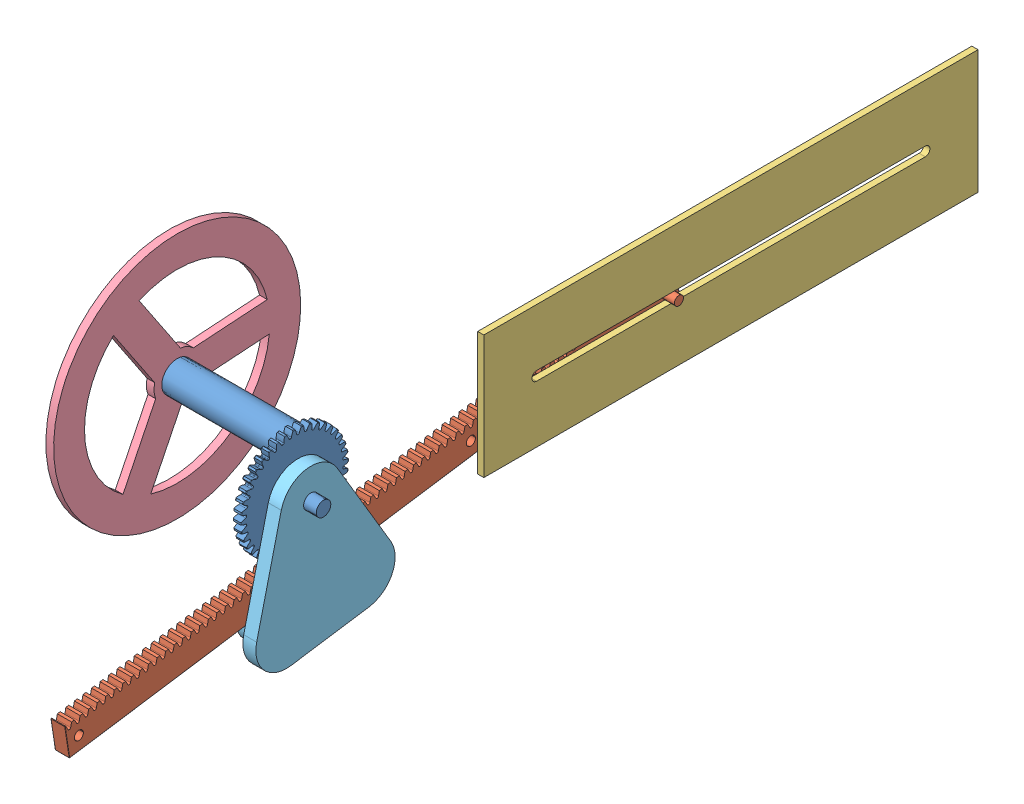
SolidWorks assembly ProgressiveSteering, configuration Default. Lengths in mm.
Overall size (68.98 136.01 372.88).
5 component instances, 5 part files, 15 mates.
Components (placement in the parent):
- SI_sdpsi_s1268z-024s040-2: SI_sdpsi_s1268z-024s040 [Default] at (1.5875 -11.3961 5.6053) x (1 0 0) z (0 -0.441363 -0.897329) size (65.8 44.45 44.45)
- SI_sdpsi_s1811y-rc-1a-1: SI_sdpsi_s1811y-rc-1a [Default] at (1.5875 -33.5524 -25.0715) x (0 -0.14912 0.988819) z (-1 0 0) size (254.01 12.19 10.85)
- slot-1: slot [Default] at (116.0145 -19.3663 -197.6025) x (0 0 1) z (-1 0 0) size (203.2 50.8 2.54)
- steering wheel-1: steering wheel [Default] at (-55.5625 0 0) x (0 0.441363 0.897329) z (1 0 0) size (101.6 101.6 3.18)
- Part1^ProgressiveSteering-1: Part1^ProgressiveSteering [Default] at (4.5085 -30.7069 -43.9399) x (0 0.14912 -0.988819) z (1 0 0) size (57.65 65.11 12.7) (virtual)
Mates (geometry in assembly coordinates):
- Coincident6: coincident anti-aligned: circle of SI_sdpsi_s1268z-024s040-2
- Coincident8: coincident: point of SI_sdpsi_s1268z-024s040-2; point of assembly
- Coincident13: coincident anti-aligned: plane of SI_sdpsi_s1268z-024s040-2 through (1.5875 -11.3961 5.6053) normal (1 0 0); plane of SI_sdpsi_s1811y-rc-1a-1 through (1.5875 -33.5524 -25.0715) normal (-1 0 0)
- Distance1: distance = 21.082 mm: line of assembly; point of SI_sdpsi_s1268z-024s040-2; line of SI_sdpsi_s1811y-rc-1a-1 through (1.5875 -47.4413 103.6472) axis (0 0.14912 -0.988819)
- RackPinionMate2: rack pinion = 45.212 mm: line of SI_sdpsi_s1811y-rc-1a-1 through (-1.3335 -20.5354 -151.4161) axis (0 -0.14912 0.988819); cylinder of SI_sdpsi_s1268z-024s040-2 through (0 -11.3961 5.6053) axis (1 0 0) radius 22.225
- Tangent1: tangent: cylinder of SI_sdpsi_s1811y-rc-1a-1 through (-1.3335 -15.8369 -168.5008) axis (-1 0 0) radius 1.8669; plane of slot-1 through (7.0485 -13.97 -252.431) normal (0 -1 0)
- Concentric6: concentric anti-aligned: cylinder of SI_sdpsi_s1268z-024s040-2 through (-50.8 0 0) axis (1 0 0) radius 6.35; cylinder of steering wheel-1 through (-50.8 0 0) axis (-1 0 0) radius 9.525
- Coincident21: coincident anti-aligned: plane of SI_sdpsi_s1268z-024s040-2 through (-50.8 0 0) normal (-1 0 0); plane of steering wheel-1 through (-50.8 0 0) normal (1 0 0)
- Coincident22: coincident: line of SI_sdpsi_s1268z-024s040-2 through (0 -31.1018 15.2978) axis (0 0.897329 -0.441363); plane of steering wheel-1 through (-55.5625 0 0) normal (0 0.441363 0.897329)
- Distance6: distance = 9.525 mm aligned: plane of slot-1 through (7.0485 9.525 -271.4599) normal (0 1 0)
- Slot1: slot anti-aligned: cylinder of SI_sdpsi_s1811y-rc-1a-1 through (-6.6139 -15.875 -146.0382) axis (1 0 0) radius 1.8669; plane of slot-1 through (7.0485 -13.97 -249.7675) normal (0 -1 0); cylinder of slot-1 through (7.0485 -15.875 -249.7675) axis (-1 0 0) radius 1.905
- Concentric7: concentric anti-aligned: cylinder of SI_sdpsi_s1268z-024s040-2 through (4.84 -11.3961 5.6053) axis (1 0 0) radius 3; cylinder of Part1^ProgressiveSteering-1 through (31.0532 -11.3961 5.6053) axis (-1 0 0) radius 3.048
- Coincident23: coincident anti-aligned: plane of SI_sdpsi_s1811y-rc-1a-1 through (4.5085 -33.5524 -25.0715) normal (1 0 0); plane of slot-1 through (4.5085 -19.3663 -197.6025) normal (-1 0 0)
- Coincident24: coincident anti-aligned: plane of SI_sdpsi_s1811y-rc-1a-1 through (4.5085 -33.5524 -25.0715) normal (1 0 0); plane of Part1^ProgressiveSteering-1 through (4.5085 -11.3961 5.6053) normal (-1 0 0)
- Parallel1: parallel anti-aligned: line of SI_sdpsi_s1811y-rc-1a-1 through (-1.3335 -20.5354 -151.4161) axis (0 -0.14912 0.988819); line of Part1^ProgressiveSteering-1 through (4.5085 -65.7633 13.8348) axis (0 0.14912 -0.988819)
